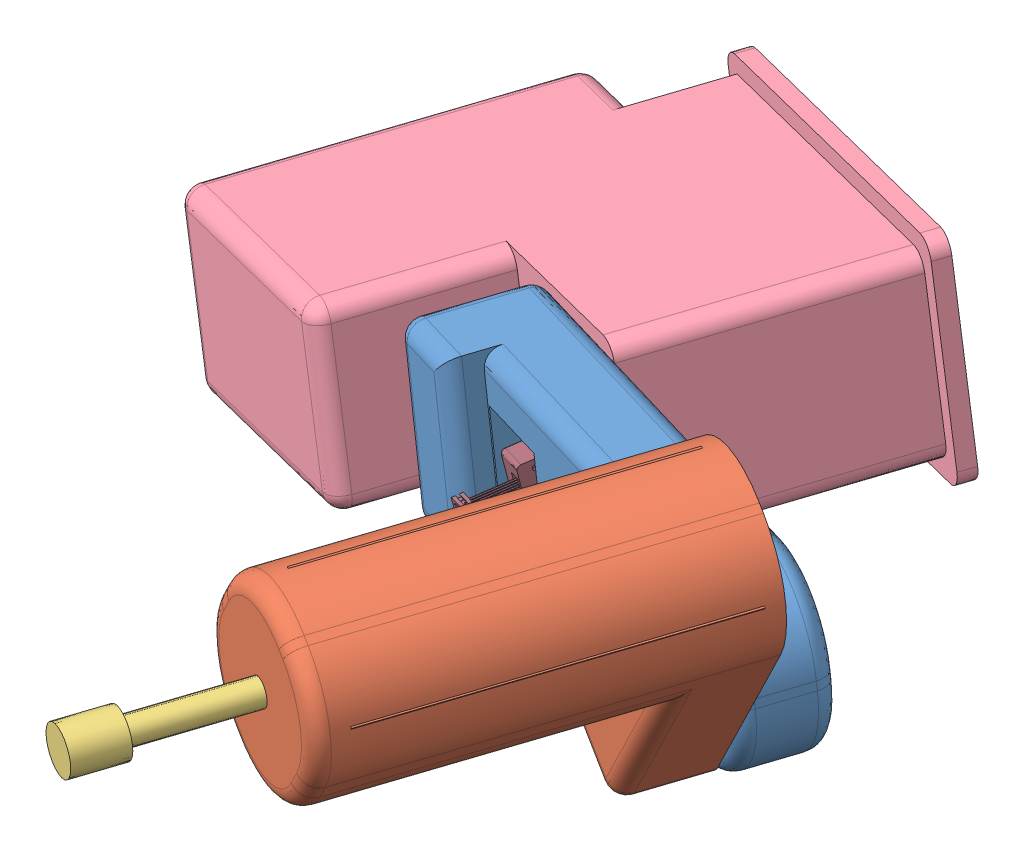
SolidWorks assembly Assem1, configuration Default. Lengths in mm.
Overall size (586.89 308.82 695.94).
37 component instances, 18 part files, 13 mates.
Components (placement in the parent):
- Arm1-1: Arm1 [Default] at (-526.8321 751.0404 -337.1447) x (0.922449 0.12837 0.364155) z (0.134554 -0.99087 0.008453) size (320 140 105)
- Arm2-1: Arm2 [Default] at (-411.5194 826.3738 -235.3115) x (0.521661 0.819005 0.238957) z (0.772585 -0.572305 0.274918) size (200 290 105)
- Arm3-1: Arm3 [Default] at (-496.2298 850.1536 52.2478) x (0.172752 -0.984683 0.023571) z (0.916064 0.169415 0.36349) size (27 330 27)
- Base2-1: Base2 [Default] at (-640.459 731.2245 -543.2435) x (0.914636 0.177379 0.363287) z (0.18016 -0.98328 0.026512) size (270 260 125)
- IR_Controller_v2.step-1: IR_Controller_v2.step [Default] at (-613.7766 723.6985 -365.85) x (-0.134554 0.99087 -0.008453) z (-0.922449 -0.12837 -0.364155) size (45.83 7.15 14.2)
- Pinion Gear Syetem Arm2-1: Pinion Gear Syetem Arm2 [Default] at (-1393.4781 -624.6005 -762.8187) x (-0.873696 0.363361 -0.323455) z (-0.361916 -0.041201 0.9313) size (61.52 59.61 54.17)
  - straight bevel gear_am-1: straight bevel gear_am [Metric - Straight bevel gear 2M 20GT 20PT 20PA 12FW ---20O30H30MD10S1] at (-262.163 -1559.3749 -30.0001) x (-0.852169 -0.523267 0) z (0.517885 -0.843404 0.143055) size (19.85 42.67 42.67)
  - straight bevel pinion_am-1: straight bevel pinion_am [Metric - Straight bevel pinion 2M20PT 20GT 20PA 12FW ---20O35H30MD10N] at (-280.9968 -1570.9396 -7.8991) x (0 0 -1) z (0.995257 -0.097283 0) size (19.85 42.67 42.67)
- MotorFinal-2: MotorFinal [默认] at (-663.7956 729.4206 -451.5654) x (-0.914636 -0.177379 -0.363287) z (0.33242 0.18144 -0.925514) size (188.9 32 73.2)
  - 0_1 (2).stp-1: 0_1 (2).stp [Default] at origin size (188.9 32 73.2)
    - 0.stp-1: 0.stp [Default] at origin size (12 3 3)
    - 0-0.stp-1: 0-0.stp [Default] at origin size (36 10 10.01)
    - 0-1.stp-1: 0-1.stp [Default] at origin size (6 22 22)
    - 0-2.stp-1: 0-2.stp [Default] at origin size (29.95 32 32)
    - 0-3.stp-1: 0-3.stp [Default] at origin size (33.59 32 32)
    - 0-4.stp-1: 0-4.stp [Default] at origin size (20.95 30 72.2)
    - 0-5.stp-1: 0-5.stp [Default] at origin size (2.3 29.7 30)
    - 0-6.stp-1: 0-6.stp [Default] at origin size (3.5 31.47 31.66)
    - 0-7.stp-1: 0-7.stp [Default] at origin size (6.99 3.52 29.03)
    - 0-8.stp-1: 0-8.stp [Default] at origin size (2.9 31.8 31.3)
    - 0-9.stp-1: 0-9.stp [Default] at origin size (66.2 32 32)
- Pinion Gear Syetem Arm2-3: Pinion Gear Syetem Arm2 [Default] at (-1273.3018 -555.502 -625.9771) x (-0.85649 0.409097 -0.314745) z (-0.361916 -0.041201 0.9313) size (61.52 59.61 54.17)
  - straight bevel gear_am-1: straight bevel gear_am [Metric - Straight bevel gear 2M 20GT 20PT 20PA 12FW ---20O30H30MD10S1] at (-262.163 -1559.3749 -30.0001) x (-0.852169 -0.523267 0) z (0.517885 -0.843404 0.143055) size (19.85 42.67 42.67)
  - straight bevel pinion_am-1: straight bevel pinion_am [Metric - Straight bevel pinion 2M20PT 20GT 20PA 12FW ---20O35H30MD10N] at (-280.9968 -1570.9396 -7.8991) x (0 0 -1) z (0.995257 -0.097283 0) size (19.85 42.67 42.67)
- MotorFinal-3: MotorFinal [默认] at (-479.7028 757.7655 -291.6879) x (-0.922449 -0.12837 -0.364155) z (0.338945 0.182526 -0.92293) size (188.9 32 73.2)
  - 0_1 (2).stp-1: 0_1 (2).stp [Default] at origin size (188.9 32 73.2)
    - 0.stp-1: 0.stp [Default] at origin size (12 3 3)
    - 0-0.stp-1: 0-0.stp [Default] at origin size (36 10 10.01)
    - 0-1.stp-1: 0-1.stp [Default] at origin size (6 22 22)
    - 0-2.stp-1: 0-2.stp [Default] at origin size (29.95 32 32)
    - 0-3.stp-1: 0-3.stp [Default] at origin size (33.59 32 32)
    - 0-4.stp-1: 0-4.stp [Default] at origin size (20.95 30 72.2)
    - 0-5.stp-1: 0-5.stp [Default] at origin size (2.3 29.7 30)
    - 0-6.stp-1: 0-6.stp [Default] at origin size (3.5 31.47 31.66)
    - 0-7.stp-1: 0-7.stp [Default] at origin size (6.99 3.52 29.03)
    - 0-8.stp-1: 0-8.stp [Default] at origin size (2.9 31.8 31.3)
    - 0-9.stp-1: 0-9.stp [Default] at origin size (66.2 32 32)
Mates (geometry in assembly coordinates):
- Coincident10: coincident anti-aligned: plane of Arm1-1 through (-544.9278 748.9804 -290.5797) normal (-0.361916 -0.041201 0.9313); plane of Arm2-1 through (-411.5194 826.3738 -235.3115) normal (0.361916 0.041201 -0.9313)
- Concentric24: concentric anti-aligned: cylinder of Arm2-1 through (-406.6621 860.35 -178.2323) axis (0.361916 0.041201 -0.9313) radius 7.75; cylinder of Arm3-1 through (-387.6551 862.5138 -227.1422) axis (-0.361916 -0.041201 0.9313) radius 7.75
- Lock1: lock: unknown of Arm1-1; unknown of IR_Controller_v2.step-1
- Concentric26: concentric aligned: cylinder of Arm1-1 through (-621.4163 737.2364 -449.6758) axis (-0.361916 -0.041201 0.9313) radius 5; cylinder of Pinion Gear System-1/PinionGearAssem-1 through (-623.5882 736.9892 -444.0872) axis (-0.361916 -0.041201 0.9313) radius 5
- Coincident14: coincident anti-aligned: plane of Arm1-1 through (-526.8321 751.0404 -337.1447) normal (0.361916 0.041201 -0.9313); plane of Base2-1 through (-694.7463 725.0443 -403.5485) normal (-0.361916 -0.041201 0.9313)
- Lock4: lock: unknown of Pinion Gear Syetem Arm2-1/straight bevel gear_am-1; unknown of MotorFinal-2/0_1 (2).stp-1/0-0.stp-1
- Lock2: lock: unknown of Base2-1; unknown of MotorFinal-2/0_1 (2).stp-1/0-9.stp-1
- Parallel2: parallel anti-aligned: plane of Pinion Gear System-1/straight bevel gear_am-1 through (-617.4219 741.2332 -439.9407) normal (-0.33242 -0.18144 0.925514); plane of MotorFinal-2/0_1 (2).stp-1/0.stp-1 through (-637.9541 735.1573 -447.8581) normal (0.33242 0.18144 -0.925514)
- Lock7: lock: unknown of Pinion Gear Syetem Arm2-3/straight bevel gear_am-1; unknown of MotorFinal-3/0_1 (2).stp-1/0-0.stp-1
- Parallel3: parallel anti-aligned: plane of Pinion Gear Syetem Arm2-3/straight bevel gear_am-1 through (-434.4084 766.9902 -280.5971) normal (-0.338945 -0.182526 0.92293); plane of MotorFinal-3/0_1 (2).stp-1/0.stp-1 through (-453.6176 762.2348 -287.942) normal (0.338945 0.182526 -0.92293)
- Lock6: lock: unknown of Arm1-1; unknown of MotorFinal-3/0_1 (2).stp-1/0-2.stp-1
- Concentric36: concentric aligned: cylinder of Arm2-1 through (-430.9628 764.2275 -310.0429) axis (-0.361916 -0.041201 0.9313) radius 5; cylinder of Pinion Gear Syetem Arm2-3/straight bevel pinion_am-1 through (-440.771 763.1109 -284.8038) axis (-0.361916 -0.041201 0.9313) radius 5
- Coincident17: coincident anti-aligned: plane of Arm1-1 through (-544.9278 748.9804 -290.5797) normal (-0.361916 -0.041201 0.9313); plane of Arm2-1 through (-411.5194 826.3738 -235.3115) normal (0.361916 0.041201 -0.9313)
